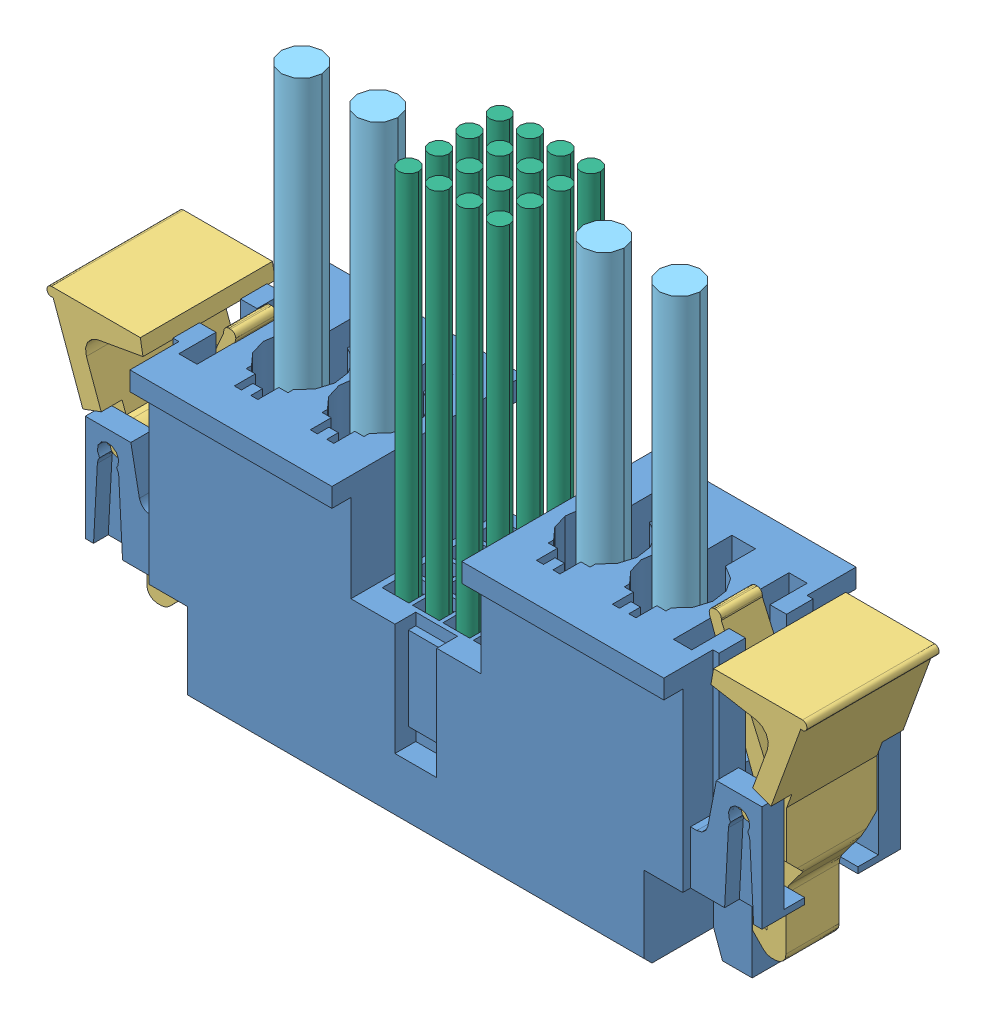
SolidWorks assembly MPTC-02-16-02-6.30-01-L-V-LC+MPCC_2_16_2_L_46_80_00_S, configuration Default. Lengths in mm.
Overall size (50.05 37.93 12.66).
24 component instances, 10 part files, 3 mates.
Components (placement in the parent):
- MPTC-02-16-02-6.30-01-L-V-LC-1: MPTC-02-16-02-6.30-01-L-V-LC [Default] at origin size (39.44 14.43 12.45) (suppressed, hidden)
  - MPTC_02_16_02_6_30_01_L_V_LC-1: MPTC_02_16_02_6_30_01_L_V_LC [Default] at (0 5.69 0) x (1 0 0) z (0 1 0) size (39.44 12.45 14.43)
    - _MPTC_02_16_02_6_30_V_LC_t_2-1: _MPTC_02_16_02_6_30_V_LC_t_2 [Default] at origin size (39.44 12.45 11.38)
    - _MPTC_02_16_02_6_30_01_V_p_4-1: _MPTC_02_16_02_6_30_01_V_p_4 [Default] at (0 0.0048 0.532) size (6.5 6.5 13.69)
    - _MPTC_01_04_01_6_30_01_L_V_c_6-1: _MPTC_01_04_01_6_30_01_L_V_c_6 [Default] at (16.255 -2.145 -4.76) x (0 1 0) z (1 0 0) size (1.42 4.7 0.25)
    - _MPTC_01_04_01_6_30_01_L_V_c_6-2: _MPTC_01_04_01_6_30_01_L_V_c_6 [Default] at (-16.255 -2.145 -4.76) x (0 1 0) z (1 0 0) size (1.42 4.7 0.25)
    - _MPTC_01_V_pp_9-1: _MPTC_01_V_pp_9 [Default] at (12.445 -2.605 -1.744) x (0 0 1) z (-1 0 0) size (13.75 7.62 2.29)
    - _MPTC_01_V_pp_9-2: _MPTC_01_V_pp_9 [Default] at (-12.445 -2.605 -1.744) x (0 0 1) z (-1 0 0) size (13.75 7.62 2.29)
    - _MPTC_01_V_pp_9-3: _MPTC_01_V_pp_9 [Default] at (7.445 -2.605 -1.744) x (0 0 1) z (-1 0 0) size (13.75 7.62 2.29)
    - _MPTC_01_V_pp_9-4: _MPTC_01_V_pp_9 [Default] at (-7.445 -2.605 -1.744) x (0 0 1) z (-1 0 0) size (13.75 7.62 2.29)
- MPCC_2_16_2_L_46_80_00_S-1: MPCC_2_16_2_L_46_80_00_S [Default] at (0 24.7 0) x (0 1 0) z (-1 0 0) size (37.93 12.66 50.05)
  - _MPC_2_16_2_C_body_2-1: _MPC_2_16_2_C_body_2 [Default] at (0 -6.33 0) x (0 0 1) z (-1 0 0) size (44.55 12.66 20.9)
  - _MPC_16__V_signal_pins_4-1: _MPC_16__V_signal_pins_4 [Default] at (-16.28 0 0) x (0 0 1) z (-1 0 0) size (7.32 6.5 10.38)
  - _LTC_22_6-1: _LTC_22_6 [Default] at (-7.3 0 20.775) x (0 -1 0) z (0 0 -1) size (8.7 17.64 9.44)
  - _LTC_22_6-2: _LTC_22_6 [Default] at (-7.3 0 -20.775) x (0 1 0) z (0 0 1) size (8.7 17.64 9.44)
  - _MPC_01_V_pp_9-1: _MPC_01_V_pp_9 [Default] at (-15.85 -2.54 -12.445) x (-1 0 0) z (0 0 -1) size (9.41 7.05 3)
  - _MPC_01_V_pp_9-2: _MPC_01_V_pp_9 [Default] at (-15.85 -2.54 -7.445) x (-1 0 0) z (0 0 -1) size (9.41 7.05 3)
  - _MPC_01_V_pp_9-3: _MPC_01_V_pp_9 [Default] at (-15.85 -2.54 7.445) x (-1 0 0) z (0 0 -1) size (9.41 7.05 3)
  - _MPC_01_V_pp_9-4: _MPC_01_V_pp_9 [Default] at (-15.85 -2.54 12.445) x (-1 0 0) z (0 0 -1) size (9.41 7.05 3)
  - _DWC_14_1_14-1: _DWC_14_1_14 [Default] at (-7.97 -0.15 12.445) x (0 0 1) z (-1 0 0) size (2.67 2.67 25)
  - _DWC_14_1_14-2: _DWC_14_1_14 [Default] at (-7.97 -0.15 7.445) x (0 0 1) z (-1 0 0) size (2.67 2.67 25)
  - _DWC_14_1_14-3: _DWC_14_1_14 [Default] at (-7.97 -0.15 -7.445) x (0 0 1) z (-1 0 0) size (2.67 2.67 25)
  - _DWC_14_1_14-4: _DWC_14_1_14 [Default] at (-7.97 -0.15 -12.445) x (0 0 1) z (-1 0 0) size (2.67 2.67 25)
  - _DWC_26_16_19-1: _DWC_26_16_19 [Default] at (-8.97 -2.555 0) x (0 0 1) z (-1 0 0) size (8 8 26)
Mates (geometry in assembly coordinates):
- Width1: width: plane of MPTC-02-16-02-6.30-01-L-V-LC-1/MPTC_02_16_02_6_30_01_L_V_LC-1/_MPTC_02_16_02_6_30_V_LC_t_2-1 through (15.291 6.3 -5.336) normal (0 0 1); plane of MPTC-02-16-02-6.30-01-L-V-LC-1/MPTC_02_16_02_6_30_01_L_V_LC-1/_MPTC_02_16_02_6_30_V_LC_t_2-1 through (-15.291 6.3 5.336) normal (0 0 -1); plane of MPCC_2_16_2_L_46_80_00_S-1/_MPC_2_16_2_C_body_2-1 through (-17.575 23.45 -5.08) normal (0 0 -1); plane of MPCC_2_16_2_L_46_80_00_S-1/_MPC_2_16_2_C_body_2-1 through (17.575 23.45 5.08) normal (0 0 1)
- Width2: width: plane of MPCC_2_16_2_L_46_80_00_S-1/_MPC_2_16_2_C_body_2-1 through (-17.575 15.015 6.33) normal (-1 0 0); plane of MPCC_2_16_2_L_46_80_00_S-1/_MPC_2_16_2_C_body_2-1 through (17.575 15.015 -6.33) normal (1 0 0); plane of MPTC-02-16-02-6.30-01-L-V-LC-1/MPTC_02_16_02_6_30_01_L_V_LC-1/_MPTC_02_16_02_6_30_V_LC_t_2-1 through (-17.831 11.38 -4.824) normal (1 0 0); plane of MPTC-02-16-02-6.30-01-L-V-LC-1/MPTC_02_16_02_6_30_01_L_V_LC-1/_MPTC_02_16_02_6_30_V_LC_t_2-1 through (17.831 11.38 0.764) normal (-1 0 0)
- Coincident1: coincident: plane of MPTC-02-16-02-6.30-01-L-V-LC-1/MPTC_02_16_02_6_30_01_L_V_LC-1/_MPTC_02_16_02_6_30_V_LC_t_2-1 through (0 6.3 0) normal (0 1 0); plane of MPCC_2_16_2_L_46_80_00_S-1/_MPC_2_16_2_C_body_2-1 through (15.035 6.3 -6.33) normal (0 -1 0)
